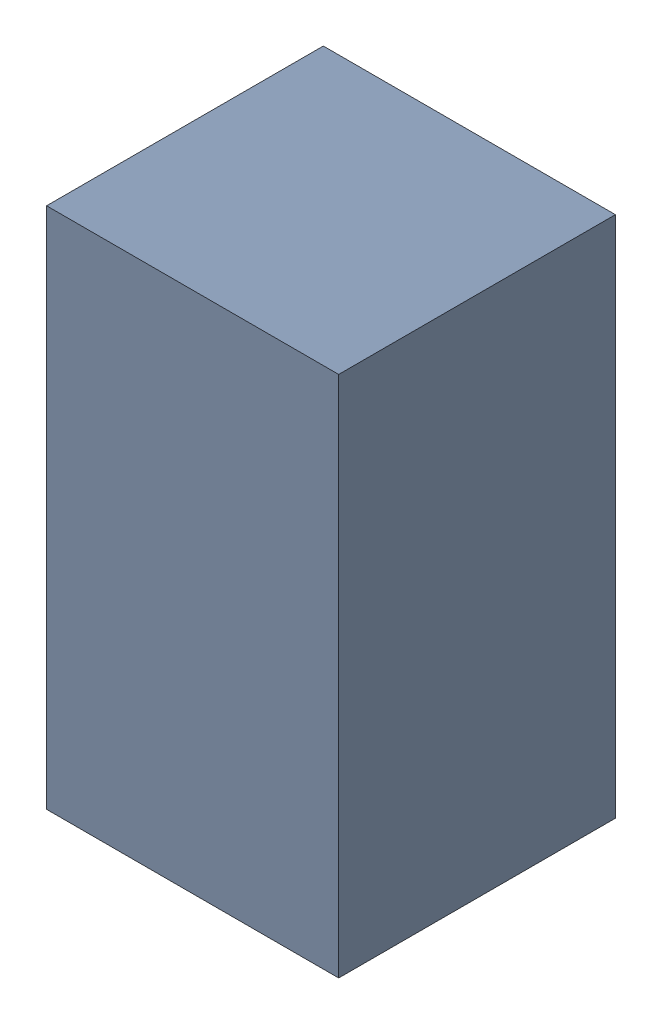
SolidWorks assembly R3, configuration Default. Lengths in mm.
Overall size (0.95 1.7 0.9).
2 component instances, 1 part files, 0 mates.
Components (placement in the parent):
- 4438511040-1: 4438511040 [Default] at (19.685 10.656 0) size (0.95 1.7 0.9)
  - Extruded_2-1: Extruded_2 [Default] at origin size (0.95 1.7 0.9)
